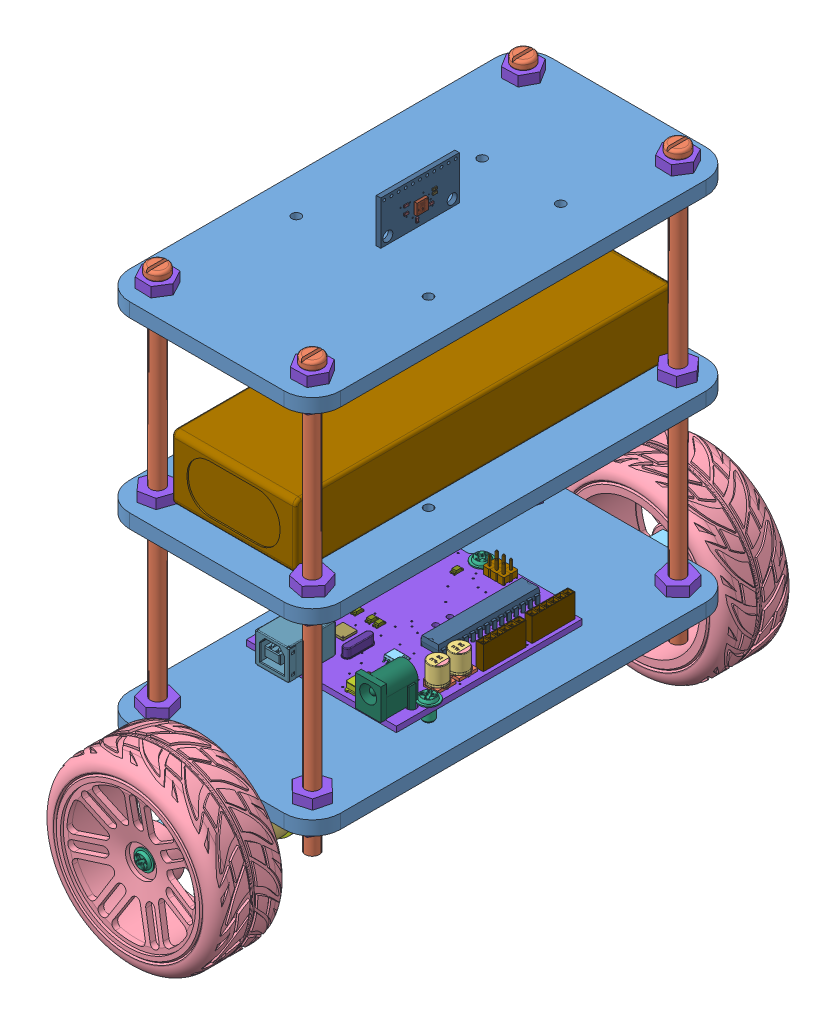
SolidWorks assembly Assem_self_balancing, configuration Default. Lengths in mm.
Overall size (90.35 207.38 206).
92 component instances, 31 part files, 47 mates.
Components (placement in the parent):
- chasis boad-1: chasis boad [Default] x (0 1 0) z (0 0 1) size (5 75 150)
- rod-1: rod [Default] at (27.5 -11.5 65) size (7.5 153.07 7.64)
- chasis boad-2: chasis boad [Default] at (0 65 0) x (0 1 0) z (0 0 1) size (5 75 150)
- chasis boad-3: chasis boad [Default] at (0 130 0) x (0 1 0) z (0 0 1) size (5 75 150)
- rod-2: rod [Default] at (27.5 -11.5 -65) size (7.5 153.07 7.64)
- rod-3: rod [Default] at (-27.5 -11.5 65) x (-1 0 0) z (0 0 -1) size (7.5 153.07 7.64)
- rod-4: rod [Default] at (-27.5 -11.5 -65) x (-1 0 0) z (0 0 -1) size (7.5 153.07 7.64)
- Motor_wheel-1: Motor_wheel [Default] at (5.9597 -85.0504 65.7158) x (0 0 1) z (-0.587075 0.809533 0) size (78 64.74 64.63)
  - Dc_motor-1: Dc_motor [Default] at (-40.7158 38.0614 62.6354) size (63.5 24.5 24.5)
  - Wheel_assembly-1: Wheel_assembly [Default] at (72.7422 1.1074 40.5957) x (0 0 1) z (-1 0 0) size (64.63 64.74 26)
    - wheel-1: wheel [Default] at (22.0397 36.954 35.458) size (64.63 64.74 26)
    - wheel_connector-1: wheel_connector [Default] at (22.0397 36.954 58.458) x (-0.5 -0.866025 0) z (0 0 -1) size (13.86 12 15)
    - Wheet_nut-1: Wheet_nut [Default] at (22.0397 36.954 41.458) x (1 0 0) z (0 1 0) size (7 8.75 7)
- clamp-1: clamp [Default] at (0 -12 25) x (-1 0 0) z (0 0 1) size (50 25 30)
- clamp-2: clamp [Default] at (0 -12 -55) x (-1 0 0) z (0 0 1) size (50 25 30)
- Motor_wheel-2: Motor_wheel [Default] at (67.7108 -40.2684 -65.7158) x (0 0 -1) z (-0.587075 0.809533 0) size (78 64.74 64.63)
  - Dc_motor-1: Dc_motor [Default] at (-40.7158 38.0614 62.6354) size (63.5 24.5 24.5)
  - Wheel_assembly-1: Wheel_assembly [Default] at (72.7422 1.1074 40.5957) x (0 0 1) z (-1 0 0) size (64.63 64.74 26)
    - wheel-1: wheel [Default] at (22.0397 36.954 35.458) size (64.63 64.74 26)
    - wheel_connector-1: wheel_connector [Default] at (22.0397 36.954 58.458) x (-0.5 -0.866025 0) z (0 0 -1) size (13.86 12 15)
    - Wheet_nut-1: Wheet_nut [Default] at (22.0397 36.954 41.458) x (1 0 0) z (0 1 0) size (7 8.75 7)
- Final-1: Final [Predeterminado] at (26.67 9 34.29) x (0 0 -1) z (1 0 0) size (74.75 15.43 53.34)
  - PCB_Final-1: PCB_Final [Default] at origin size (68.58 2 53.34)
  - Header Vertical 2.54mm Pitch2-1: Header Vertical 2.54mm Pitch2 [Header 6 Way] at (62.2731 2 -29.1415) size (5.08 8.88 7.62)
  - IC DIP 28-1: IC DIP 28 [Default] at (51.4233 4.3498 -16.4837) x (0 0.005002 0.999987) z (-1 0 0) size (7.87 6.22 35.94)
  - User Library-QFN32 (FTDI)-1: User Library-QFN32 (FTDI) [Default] at (19.2089 2.05 -38.1588) x (-1 0 0) z (0 1 0) size (5 5 0.85)
    - User Library-QFN32 (FTDI)_Anschl_X_FCsse_1-1: User Library-QFN32 (FTDI)_Anschl_X_FCsse_1 [Default] x (0 -1 0) z (0 0 1) size (5 5 0.2)
    - User Library-QFN32 (FTDI)_K_X_F6rper_1-1: User Library-QFN32 (FTDI)_K_X_F6rper_1 [Default] at origin size (5 5 0.8)
    - User Library-QFN32 (FTDI)_Beschriftung_1-1: User Library-QFN32 (FTDI)_Beschriftung_1 [Default] at origin size (0.51 0.51 0.05)
  - User Library-67068-0000-molex-1: User Library-67068-0000-molex [Default] at (-6.1546 2 -38.0545) x (0.002421 0 0.999997) z (-0.999997 0 0.002421) size (14.9 15.43 17)
  - User Library-dc range - dc connector[4840_2201]-1: User Library-dc range - dc connector[4840_2201] [Default] at (11.794 2 -12.8354) x (0 0 1) z (-1 0 0) size (9.51 14.5 13.83)
  - LED 1206-2: LED 1206 [Default] at (28.1068 2 -36.9237) x (0 0 -1) z (1 0 0) size (1.6 1.1 3.2)
  - LED 1206-3: LED 1206 [Default] at (28.142 2 -34.2868) x (0 0 -1) z (1 0 0) size (1.6 1.1 3.2)
  - LED 1206-4: LED 1206 [Default] at (58.3346 2 -36.8813) x (0 0 -1) z (1 0 0) size (1.6 1.1 3.2)
  - LED 1206-5: LED 1206 [Default] at (28.1068 2 -41.994) x (0 0 -1) z (1 0 0) size (1.6 1.1 3.2)
  - XTAL Small-1: XTAL Small [Default] at (14.2222 2 -30.4346) x (1 0 0) z (0 1 0) size (10.67 3.05 5.63)
  - Stackable Female Pin Header-1: Stackable Female Pin Header [6 Way] at (50.8347 2 -2.5872) size (15.24 8.3 2.54)
  - Stackable Female Pin Header-2: Stackable Female Pin Header [Default] at (45.7158 1.1368 -50.806) size (20.32 8.3 2.54)
  - Stackable Female Pin Header-3: Stackable Female Pin Header [Default] at (23.9415 1.1201 -50.7298) size (20.32 8.3 2.54)
  - Stackable Female Pin Header-4: Stackable Female Pin Header [6 Way] at (33.5006 2 -2.5872) size (15.24 8.3 2.54)
  - User Library-ALU-D8-1: User Library-ALU-D8 [Default] at (20.4464 1.8 -5.7935) x (0 0 -1) z (0 1 0) size (7 6.6 7.71)
    - User Library-ALU-D8_Pins_1-1: User Library-ALU-D8_Pins_1 [Default] at origin size (7 0.65 0.4)
    - User Library-ALU-D8_Fuss_1-1: User Library-ALU-D8_Fuss_1 [Default] at origin size (6.6 6.6 1)
    - User Library-ALU-D8_K_X_F6rper_1-1: User Library-ALU-D8_K_X_F6rper_1 [Default] at origin size (6.3 6.3 7)
    - User Library-ALU-D8_Beschriftung_1-1: User Library-ALU-D8_Beschriftung_1 [Default] at origin size (4.36 4.98 0.11)
  - User Library-ALU-D8-2: User Library-ALU-D8 [Default] at (28.1214 1.8 -5.7935) x (0 0 -1) z (0 1 0) size (7 6.6 7.71)
    - User Library-ALU-D8_Pins_1-1: User Library-ALU-D8_Pins_1 [Default] at origin size (7 0.65 0.4)
    - User Library-ALU-D8_Fuss_1-1: User Library-ALU-D8_Fuss_1 [Default] at origin size (6.6 6.6 1)
    - User Library-ALU-D8_K_X_F6rper_1-1: User Library-ALU-D8_K_X_F6rper_1 [Default] at origin size (6.3 6.3 7)
    - User Library-ALU-D8_Beschriftung_1-1: User Library-ALU-D8_Beschriftung_1 [Default] at origin size (4.36 4.98 0.11)
  - User Library-SOIC-8-1: User Library-SOIC-8 [Default] at (20.4108 1.85 -20.3024) x (0 0 -1) z (1 0 0) size (5 1.75 6.01)
    - User Library-SOIC-8_SOIC-8_Body_1-1: User Library-SOIC-8_SOIC-8_Body_1 [Default] at origin size (5 1.6 4)
    - User Library-SOIC-8_SOIC-8_Pins_1-1: User Library-SOIC-8_SOIC-8_Pins_1 [Default] at origin size (4.23 0.99 6.01)
  - SO 369A-1: SO 369A [Standard] at (5.5398 2 -17.4191) x (0 0 -1) z (0 1 0) size (6.6 10.1 2.4)
- Wheet_nut-1: Wheet_nut [Default] at (19.05 11 -31.75) size (7 8.75 7)
- Wheet_nut-3: Wheet_nut [Default] at (24.13 11 20.32) x (0.50067 0 0.865638) z (-0.865638 0 0.50067) size (7 8.75 7)
- Wheet_nut-4: Wheet_nut [Default] at (-24.13 11 19.05) x (-0.998351 0 0.057411) z (-0.057411 0 -0.998351) size (7 8.75 7)
- Wheet_nut-5: Wheet_nut [Default] at (-8.89 11 -31.75) x (-0.998351 0 0.057411) z (-0.057411 0 -0.998351) size (7 8.75 7)
- Nut-1: Nut [Default] at (27.5 135 65) x (0.99941 0 -0.034339) z (0.034339 0 0.99941) size (11.55 3.5 10)
- Nut-2: Nut [Default] at (27.5 126.5 65) x (0.99941 0 -0.034339) z (0.034339 0 0.99941) size (11.55 3.5 10)
- Nut-3: Nut [Default] at (27.5 70 65) x (0.980629 0 0.195872) z (-0.195872 0 0.980629) size (11.55 3.5 10)
- Nut-4: Nut [Default] at (27.5 61.5 65) x (0.99941 0 -0.034339) z (0.034339 0 0.99941) size (11.55 3.5 10)
- Nut-5: Nut [Default] at (27.5 5 65) x (0.962307 0 -0.271966) z (0.271966 0 0.962307) size (11.55 3.5 10)
- Nut-6: Nut [Default] at (27.5 -3.5 65) x (0.99941 0 -0.034339) z (0.034339 0 0.99941) size (11.55 3.5 10)
- Nut-7: Nut [Default] at (27.5 135 -65) x (0.99941 0 0.034339) z (-0.034339 0 0.99941) size (11.55 3.5 10)
- Nut-8: Nut [Default] at (27.5 126.5 -65) x (0.99941 0 0.034339) z (-0.034339 0 0.99941) size (11.55 3.5 10)
- Nut-9: Nut [Default] at (27.5 70 -65) x (0.980629 0 -0.195872) z (0.195872 0 0.980629) size (11.55 3.5 10)
- Nut-10: Nut [Default] at (27.5 61.5 -65) x (0.99941 0 0.034339) z (-0.034339 0 0.99941) size (11.55 3.5 10)
- Nut-11: Nut [Default] at (27.5 5 -65) x (0.962307 0 0.271966) z (-0.271966 0 0.962307) size (11.55 3.5 10)
- Nut-12: Nut [Default] at (27.5 -3.5 -65) x (0.99941 0 0.034339) z (-0.034339 0 0.99941) size (11.55 3.5 10)
- Nut-13: Nut [Default] at (-27.5 135 65) x (-0.99941 0 -0.034339) z (0.034339 0 -0.99941) size (11.55 3.5 10)
- Nut-14: Nut [Default] at (-27.5 126.5 65) x (-0.99941 0 -0.034339) z (0.034339 0 -0.99941) size (11.55 3.5 10)
- Nut-15: Nut [Default] at (-27.5 70 65) x (-0.980629 0 0.195872) z (-0.195872 0 -0.980629) size (11.55 3.5 10)
- Nut-16: Nut [Default] at (-27.5 61.5 65) x (-0.99941 0 -0.034339) z (0.034339 0 -0.99941) size (11.55 3.5 10)
- Nut-17: Nut [Default] at (-27.5 5 65) x (-0.962307 0 -0.271966) z (0.271966 0 -0.962307) size (11.55 3.5 10)
- Nut-18: Nut [Default] at (-27.5 -3.5 65) x (-0.99941 0 -0.034339) z (0.034339 0 -0.99941) size (11.55 3.5 10)
- Nut-19: Nut [Default] at (-27.5 135 -65) x (-0.99941 0 0.034339) z (-0.034339 0 -0.99941) size (11.55 3.5 10)
- Nut-20: Nut [Default] at (-27.5 126.5 -65) x (-0.99941 0 0.034339) z (-0.034339 0 -0.99941) size (11.55 3.5 10)
- Nut-21: Nut [Default] at (-27.5 70 -65) x (-0.980629 0 -0.195872) z (0.195872 0 -0.980629) size (11.55 3.5 10)
- Nut-22: Nut [Default] at (-27.5 61.5 -65) x (-0.99941 0 0.034339) z (-0.034339 0 -0.99941) size (11.55 3.5 10)
- Nut-23: Nut [Default] at (-27.5 5 -65) x (-0.962307 0 0.271966) z (-0.271966 0 -0.962307) size (11.55 3.5 10)
- Nut-24: Nut [Default] at (-27.5 -3.5 -65) x (-0.99941 0 0.034339) z (-0.034339 0 -0.99941) size (11.55 3.5 10)
- Turnigy_2650mAh_4S__nano_tech_Lipo_Battery-1: Turnigy_2650mAh_4S__nano_tech_Lipo_Battery [Default] at (-0.5 78 -4) x (0 0 1) z (0 -1 0) size (135 44 23)
- MPU-9150_(Assembly)-1: MPU-9150_(Assembly) [Default] at (-13.8539 108.3434 6.3322) x (0 -1 0) z (1 0 0) size (15.5 27.94 2.61)
  - MPU-9150_(CI_Board)-1: MPU-9150_(CI_Board) [Default] at (-34.4066 6.3322 13.0539) size (15.5 27.94 1.6)
  - MPU-9150_(Chip)-1: MPU-9150_(Chip) [Default] at (-33.0677 6.2642 14.7899) size (4 4 1.02)
  - MPU-9150_(0603_SMD1)-2: MPU-9150_(0603_SMD1) [Valor predeterminado] at (-34.3875 11.2906 14.8824) x (0 1 0) z (1 0 0) size (1.52 0.46 0.77)
  - MPU-9150_(0603_SMD1)-5: MPU-9150_(0603_SMD1) [Valor predeterminado] at (-35.6777 11.3028 14.8824) x (0 1 0) z (1 0 0) size (1.52 0.46 0.77)
  - MPU-9150_(0603_SMD2)-1: MPU-9150_(0603_SMD2) [Valor predeterminado] at (-29.1609 5.0488 14.8824) x (1 0 0) z (0 1 0) size (1.52 0.46 0.77)
  - MPU-9150_(0603_SMD2)-2: MPU-9150_(0603_SMD2) [Valor predeterminado] at (-35.5953 1.1542 14.8824) x (0 1 0) z (-1 0 0) size (1.52 0.46 0.77)
  - MPU-9150_(0603_SMD2)-3: MPU-9150_(0603_SMD2) [Valor predeterminado] at (-33.0357 1.1509 14.8824) x (0 1 0) z (-1 0 0) size (1.52 0.46 0.77)
  - MPU-9150_(0603_SMD2)-4: MPU-9150_(0603_SMD2) [Valor predeterminado] at (-31.762 10.0881 14.8824) x (0 1 0) z (-1 0 0) size (1.52 0.46 0.77)
Mates (geometry in assembly coordinates):
- Coincident1: coincident anti-aligned: plane of chasis boad-1; plane of assembly through (0 0 0) normal (1 0 0)
- Coincident2: coincident aligned: plane of chasis boad-1; plane of assembly through (0 0 0) normal (0 1 0)
- Coincident3: coincident aligned: plane of chasis boad-1 through (0 0 0) normal (0 0 1); plane of assembly through (0 0 0) normal (0 0 1)
- Concentric1: concentric aligned: cylinder of chasis boad-1 through (27.5 5 65) axis (0 -1 0) radius 2.5; cylinder of rod-1 through (27.5 138.5 65) axis (0 -1 0) radius 2.5
- Concentric2: concentric aligned: cylinder of rod-1 through (27.5 138.5 65) axis (0 -1 0) radius 2.5; cylinder of chasis boad-2 through (27.5 70 65) axis (0 -1 0) radius 2.5
- Concentric3: concentric aligned: cylinder of rod-1 through (27.5 138.5 65) axis (0 -1 0) radius 2.5; cylinder of chasis boad-3 through (27.5 135 65) axis (0 -1 0) radius 2.5
- Coincident5: coincident aligned: plane of chasis boad-1 through (37.5 5 65) normal (1 0 0); plane of chasis boad-2 through (37.5 70 65) normal (1 0 0)
- Coincident6: coincident aligned: plane of chasis boad-2 through (37.5 70 65) normal (1 0 0); plane of chasis boad-3 through (37.5 135 65) normal (1 0 0)
- Distance2: distance = 60 mm anti-aligned: plane of chasis boad-1 through (-27.5 5 -65) normal (0 1 0); plane of chasis boad-2 through (-27.5 65 -65) normal (0 -1 0)
- Distance3: distance = 60 mm anti-aligned: plane of chasis boad-3 through (-27.5 130 -65) normal (0 -1 0); plane of chasis boad-2 through (-27.5 70 -65) normal (0 1 0)
- Tangent1: tangent anti-aligned: plane of chasis boad-1 through (-27.5 0 -65) normal (0 -1 0); cylinder of Motor_wheel-1/Dc_motor-1 through (0 -12 56) axis (0 0 -1) radius 12
- Coincident10: coincident anti-aligned: plane of chasis boad-1 through (-27.5 0 -65) normal (0 -1 0); plane of clamp-1 through (-18.3303 0 55) normal (0 1 0)
- Distance4: distance = 20 mm aligned: plane of clamp-1 through (18.3303 -7 55) normal (0 0 1); plane of chasis boad-1 through (-27.5 5 75) normal (0 0 1)
- Coincident12: coincident anti-aligned: plane of clamp-1; plane of assembly through (0 0 0) normal (1 0 0)
- Concentric4: concentric aligned: cylinder of Motor_wheel-1/Dc_motor-1 through (0 -12 56) axis (0 0 -1) radius 12; cylinder of clamp-1 through (0 -12 55) axis (0 0 -1) radius 12
- Coincident13: coincident aligned: plane of Motor_wheel-1/Dc_motor-1 through (0 -12 25) normal (0 0 -1); plane of clamp-1 through (18.3303 -7 25) normal (0 0 -1)
- Concentric5: concentric anti-aligned: cylinder of chasis boad-1 through (-8.89 0 -31.75) axis (0 1 0) radius 1.6; cylinder of Final-1/PCB_Final-1 through (-8.89 11 -31.75) axis (0 -1 0) radius 1.6
- Concentric6: concentric anti-aligned: cylinder of chasis boad-1 through (19.05 0 -31.75) axis (0 1 0) radius 1.6; cylinder of Final-1/PCB_Final-1 through (19.05 11 -31.75) axis (0 -1 0) radius 1.6
- Parallel1: parallel aligned: cylinder of chasis boad-1 through (24.13 0 20.32) axis (0 1 0) radius 1.6; cylinder of Final-1/PCB_Final-1 through (18.1648 4.1917 22.3914) axis (0 1 0) radius 1.7
- Concentric8: concentric anti-aligned: cylinder of Final-1/PCB_Final-1 through (19.05 11 -31.75) axis (0 -1 0) radius 1.6; cylinder of Wheet_nut-1 through (19.05 5 -31.75) axis (0 1 0) radius 2
- Coincident14: coincident anti-aligned: plane of Final-1/PCB_Final-1 through (26.67 11 34.29) normal (0 1 0); plane of Wheet_nut-1 through (19.05 11 -31.75) normal (0 -1 0)
- Coincident15: coincident anti-aligned: plane of chasis boad-1 through (-27.5 5 -65) normal (0 1 0); plane of Wheet_nut-1 through (19.05 5 -31.75) normal (0 -1 0)
- Concentric10: concentric anti-aligned: cylinder of Final-1/PCB_Final-1 through (24.13 11 20.32) axis (0 -1 0) radius 1.6; cylinder of Wheet_nut-3 through (24.13 5 20.32) axis (0 1 0) radius 2
- Coincident16: coincident anti-aligned: plane of chasis boad-1 through (-27.5 5 -65) normal (0 1 0); plane of Wheet_nut-3 through (24.13 5 20.32) normal (0 -1 0)
- Concentric11: concentric anti-aligned: cylinder of Final-1/PCB_Final-1 through (-24.13 11 19.05) axis (0 -1 0) radius 1.6; cylinder of Wheet_nut-4 through (-24.13 5 19.05) axis (0 1 0) radius 2
- Coincident17: coincident anti-aligned: plane of chasis boad-1 through (-27.5 5 -65) normal (0 1 0); plane of Wheet_nut-4 through (-24.13 5 19.05) normal (0 -1 0)
- Concentric12: concentric anti-aligned: cylinder of Final-1/PCB_Final-1 through (-8.89 11 -31.75) axis (0 -1 0) radius 1.6; cylinder of Wheet_nut-5 through (-8.89 5 -31.75) axis (0 1 0) radius 2
- Coincident18: coincident anti-aligned: plane of chasis boad-1 through (-27.5 5 -65) normal (0 1 0); plane of Wheet_nut-5 through (-8.89 5 -31.75) normal (0 -1 0)
- Concentric13: concentric aligned: cylinder of rod-1 through (27.5 138.5 65) axis (0 -1 0) radius 2.5; cylinder of Nut-1 through (27.5 138.5 65) axis (0 -1 0) radius 2.5
- Coincident19: coincident anti-aligned: plane of chasis boad-3 through (-27.5 135 -65) normal (0 1 0); plane of Nut-1 through (27.5 135 65) normal (0 -1 0)
- Concentric14: concentric aligned: cylinder of rod-1 through (27.5 138.5 65) axis (0 -1 0) radius 2.5; cylinder of Nut-2 through (27.5 130 65) axis (0 -1 0) radius 2.5
- Coincident20: coincident anti-aligned: plane of chasis boad-3 through (-27.5 130 -65) normal (0 -1 0); plane of Nut-2 through (27.5 130 65) normal (0 1 0)
- Concentric15: concentric aligned: cylinder of rod-1 through (27.5 138.5 65) axis (0 -1 0) radius 2.5; cylinder of Nut-3 through (27.5 73.5 65) axis (0 -1 0) radius 2.5
- Coincident21: coincident anti-aligned: plane of chasis boad-2 through (-27.5 70 -65) normal (0 1 0); plane of Nut-3 through (27.5 70 65) normal (0 -1 0)
- Concentric16: concentric aligned: cylinder of rod-1 through (27.5 138.5 65) axis (0 -1 0) radius 2.5; cylinder of Nut-4 through (27.5 65 65) axis (0 -1 0) radius 2.5
- Coincident22: coincident anti-aligned: plane of chasis boad-2 through (-27.5 65 -65) normal (0 -1 0); plane of Nut-4 through (27.5 65 65) normal (0 1 0)
- Concentric17: concentric aligned: cylinder of rod-1 through (27.5 138.5 65) axis (0 -1 0) radius 2.5; cylinder of Nut-5 through (27.5 8.5 65) axis (0 -1 0) radius 2.5
- Coincident23: coincident anti-aligned: plane of chasis boad-1 through (-27.5 5 -65) normal (0 1 0); plane of Nut-5 through (27.5 5 65) normal (0 -1 0)
- Concentric18: concentric aligned: cylinder of rod-1 through (27.5 138.5 65) axis (0 -1 0) radius 2.5; cylinder of Nut-6 through (27.5 0 65) axis (0 -1 0) radius 2.5
- Coincident24: coincident anti-aligned: plane of chasis boad-1 through (-27.5 0 -65) normal (0 -1 0); plane of Nut-6 through (27.5 0 65) normal (0 1 0)
- Coincident26: coincident anti-aligned: plane of chasis boad-2 through (-27.5 70 -65) normal (0 1 0); plane of Turnigy_2650mAh_4S__nano_tech_Lipo_Battery-1 through (-0.5 70 -4) normal (0 -1 0)
- Distance6: distance = 16 mm aligned: plane of Turnigy_2650mAh_4S__nano_tech_Lipo_Battery-1 through (21.5 70 65) normal (1 0 0); plane of chasis boad-2 through (37.5 70 65) normal (1 0 0)
- Distance7: distance = 10 mm aligned: plane of Turnigy_2650mAh_4S__nano_tech_Lipo_Battery-1 through (-22.5 70 65) normal (0 0 1); plane of chasis boad-2 through (-27.5 70 75) normal (0 0 1)
- Coincident30: coincident anti-aligned: plane of rod-1 through (27.5 138.5 65) normal (0 -1 0); plane of Nut-1 through (27.5 138.5 65) normal (0 1 0)
- Coincident31: coincident anti-aligned: plane of chasis boad-3 through (-27.5 135 -65) normal (0 1 0); plane of MPU-9150_(Assembly)-1/MPU-9150_(CI_Board)-1 through (0.8 135 13.97) normal (0 -1 0)
- Coincident32: coincident aligned: plane of MPU-9150_(Assembly)-1/MPU-9150_(CI_Board)-1 through (0 142.75 0) normal (1 0 0); plane of assembly through (0 0 0) normal (1 0 0)
- Coincident33: coincident aligned: plane of MPU-9150_(Assembly)-1/MPU-9150_(CI_Board)-1; plane of assembly through (0 0 0) normal (0 0 1)
